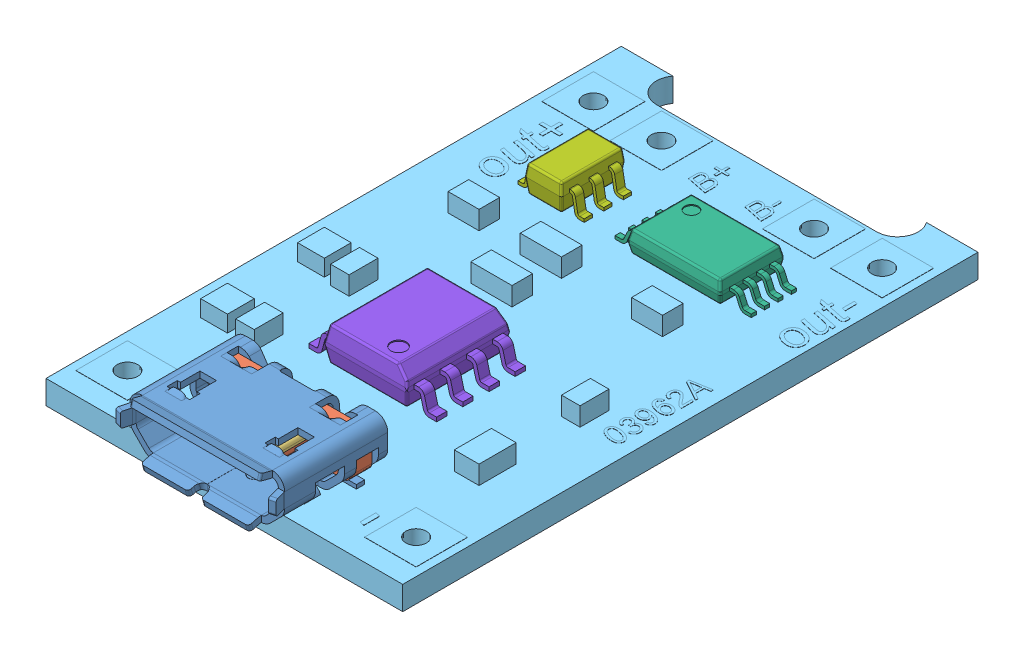
SolidWorks assembly 03962A, configuration По умолчанию. Lengths in mm.
Overall size (17.3 3.8 29.35).
13 component instances, 8 part files, 13 mates.
Components (placement in the parent):
- Копия micro_usb_connector^Плата ЗУ TP4056(03962A)-1: Копия micro_usb_connector^Плата ЗУ TP4056(03962A) [По умолчанию] at (4.4684 3.5679 3.8034) x (0 0 1) z (0 1 0) size (5.84 7.77 3.44) (virtual)
  - Копия shield^Копия micro_usb_connector_Плата ЗУ TP4056(03962A)-1: Копия shield^Копия micro_usb_connector_Плата ЗУ TP4056(03962A) [По умолчанию] at origin size (5.84 7.77 3.44) (virtual)
  - Копия socket_housing^Копия micro_usb_connector_Плата ЗУ TP4056(03962A)-1: Копия socket_housing^Копия micro_usb_connector_Плата ЗУ TP4056(03962A) [По умолчанию] at origin size (4.24 6.85 2.15) (virtual)
  - Копия socket_plate^Копия micro_usb_connector_Плата ЗУ TP4056(03962A)-1: Копия socket_plate^Копия micro_usb_connector_Плата ЗУ TP4056(03962A) [По умолчанию] at origin size (3.38 6.8 0.31) (virtual)
  - Копия terminal^Копия micro_usb_connector_Плата ЗУ TP4056(03962A)-2: Копия terminal^Копия micro_usb_connector_Плата ЗУ TP4056(03962A) [По умолчанию] at (0 -1.3 0) size (3.22 0.35 1.72) (virtual)
  - Копия terminal^Копия micro_usb_connector_Плата ЗУ TP4056(03962A)-6: Копия terminal^Копия micro_usb_connector_Плата ЗУ TP4056(03962A) [По умолчанию] at (0 -0.65 0) size (3.22 0.35 1.72) (virtual)
  - Копия terminal^Копия micro_usb_connector_Плата ЗУ TP4056(03962A)-7: Копия terminal^Копия micro_usb_connector_Плата ЗУ TP4056(03962A) [По умолчанию] at origin size (3.22 0.35 1.72) (virtual)
  - Копия terminal^Копия micro_usb_connector_Плата ЗУ TP4056(03962A)-8: Копия terminal^Копия micro_usb_connector_Плата ЗУ TP4056(03962A) [По умолчанию] at (0 0.65 0) size (3.22 0.35 1.72) (virtual)
  - Копия terminal^Копия micro_usb_connector_Плата ЗУ TP4056(03962A)-9: Копия terminal^Копия micro_usb_connector_Плата ЗУ TP4056(03962A) [По умолчанию] at (0 1.3 0) size (3.22 0.35 1.72) (virtual)
- Деталь11^Плата ЗУ TP4056(03962A)-1: Деталь11^Плата ЗУ TP4056(03962A) [По умолчанию] at (4.4684 3.5679 3.8034) x (0 0 1) z (0 1 0) size (27.9 17.3 2.06) (virtual)
- Копия MO-153AA^Плата ЗУ TP4056(03962A)-1: Копия MO-153AA^Плата ЗУ TP4056(03962A) [По умолчанию] at (7.0684 3.5679 -14.7726) x (0 0 1) z (0 1 0) size (3.1 6.6 1.2) (virtual)
- Копия SC-74^Плата ЗУ TP4056(03962A)-1: Копия SC-74^Плата ЗУ TP4056(03962A) [По умолчанию] at (0.7184 3.5679 -14.7726) x (0 0 -1) z (0 1 0) size (3.1 3.2 1.45) (virtual)
- Копия MS-012AA^Плата ЗУ TP4056(03962A)-1: Копия MS-012AA^Плата ЗУ TP4056(03962A) [По умолчанию] at (4.0184 3.5679 -3.8226) x (0 0 -1) z (0 1 0) size (5 6.2 1.75) (virtual)
Mates (geometry in assembly coordinates):
- На месте1: in place: plane of ? through (4.4684 3.5679 3.8034) normal (0 1 0); plane of ? through (4.4684 3.5679 3.8034) normal (0 1 0); moOrthogonalPlaneRef_w of ? through (4.4684 3.5679 3.8034) normal (0 1 0); unknown of ?; plane of ? through (4.4684 3.5679 3.8034) normal (0 1 0); unknown of ?; plane of ? through (4.4684 3.5679 3.8034) normal (0 1 0); unknown of ?
- Совпадение1: coincident: plane of ?; plane of ?
- Совпадение2: coincident: moOrthogonalPlaneRef_w of ?; plane of ?
- Совпадение3: coincident: moOrthogonalPlaneRef_w of ?; plane of ?
- Совпадение1: coincident: plane of ? through (4.4684 3.5679 3.8034) normal (0 1 0); plane of Копия MO-153AA^Плата ЗУ TP4056(03962A)-1 through (10.3684 3.5679 -13.6726) normal (0 -1 0)
- Расстояние1: distance = 4 mm: plane of Копия MO-153AA^Плата ЗУ TP4056(03962A)-1 through (9.3184 4.1679 -16.3226) normal (0 0 -1); plane of ? through (4.4684 2.4179 -20.3226) normal (0 0 -1)
- Расстояние2: distance = 3.8 mm: plane of ? through (13.1184 2.4179 3.8034) normal (1 0 0); plane of Копия MO-153AA^Плата ЗУ TP4056(03962A)-1 through (9.3184 4.1679 -13.2226) normal (1 0 0)
- Совпадение2: coincident: plane of ? through (4.4684 3.5679 3.8034) normal (0 1 0); plane of Копия SC-74^Плата ЗУ TP4056(03962A)-1 through (-0.6663 3.5679 -15.9226) normal (0 -1 0)
- Расстояние3: distance = 4 mm: plane of ? through (4.4684 2.4179 -20.3226) normal (0 0 -1); line of Копия SC-74^Плата ЗУ TP4056(03962A)-1 through (1.5192 4.4679 -16.3226) axis (-1 0 0)
- Расстояние4: distance = 4 mm: plane of ? through (-4.1816 2.4179 3.8034) normal (-1 0 0); line of Копия SC-74^Плата ЗУ TP4056(03962A)-1 through (-0.1816 4.4679 -16.2234) axis (0 0 1)
- Совпадение3: coincident: plane of ? through (4.4684 3.5679 3.8034) normal (0 1 0); plane of Копия MS-012AA^Плата ЗУ TP4056(03962A)-1 through (0.9184 3.5679 -2.1676) normal (0 -1 0)
- Расстояние5: distance = 6.2 mm: plane of Копия MS-012AA^Плата ЗУ TP4056(03962A)-1 through (2.0184 4.3929 -6.3226) normal (-1 0 0); plane of ? through (-4.1816 2.4179 3.8034) normal (-1 0 0)
- Расстояние6: distance = 14 mm: plane of Копия MS-012AA^Плата ЗУ TP4056(03962A)-1 through (6.0184 4.3929 -6.3226) normal (0 0 -1); plane of ? through (4.4684 2.4179 -20.3226) normal (0 0 -1)
